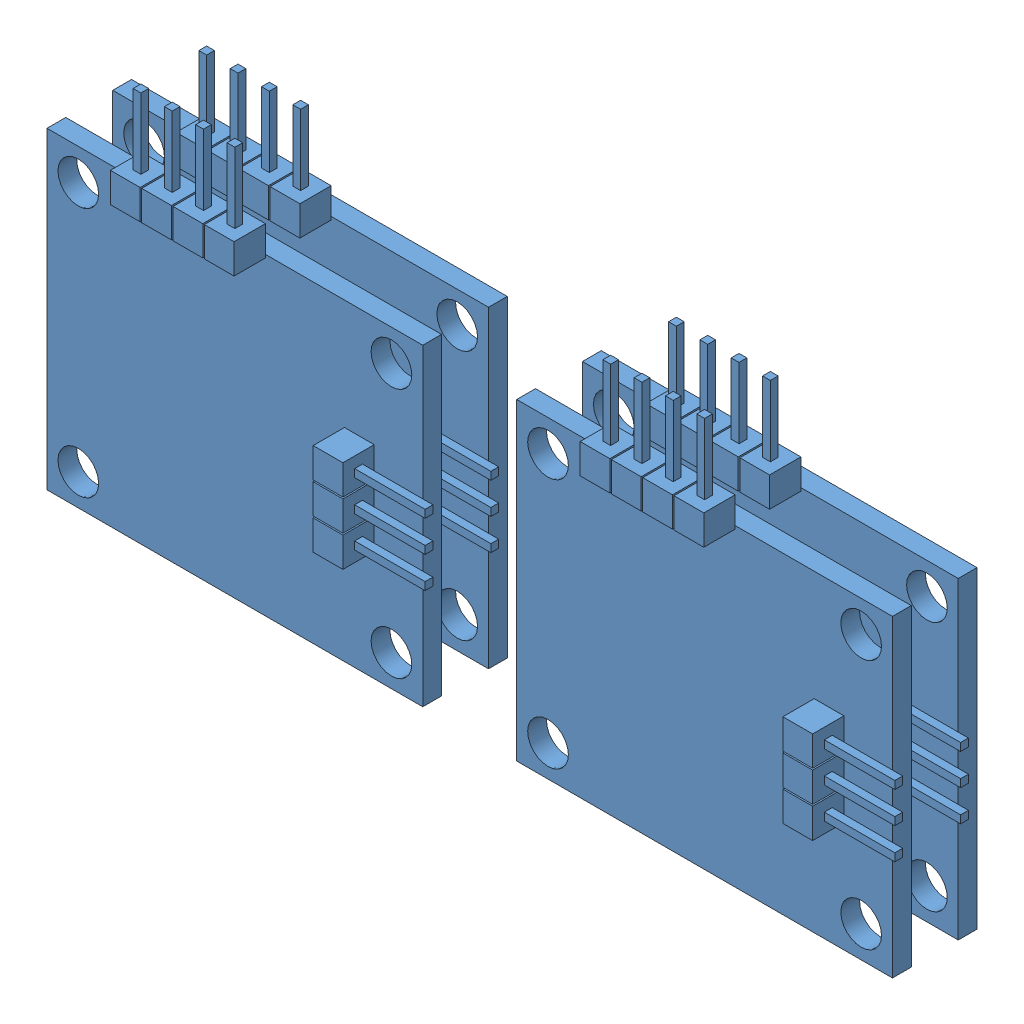
SolidWorks assembly encoderplate_group, configuration Default. Lengths in mm.
Overall size (70.36 33.27 9.4).
4 component instances, 1 part files, 57 mates.
Components (placement in the parent):
- Encoder_Plate-11: Encoder_Plate [Default] at (-18.7325 83.6117 -10.4902) x (1 0 0) z (0 1 0) size (32.26 4.06 33.27)
- Encoder_Plate-12: Encoder_Plate [Default] at (19.3675 83.6117 -10.4902) x (1 0 0) z (0 1 0) size (32.26 4.06 33.27)
- Encoder_Plate-14: Encoder_Plate [Default] at (19.3675 83.6117 -5.1562) x (1 0 0) z (0 1 0) size (32.26 4.06 33.27)
- Encoder_Plate-15: Encoder_Plate [Default] at (-18.7325 83.6117 -5.1562) x (1 0 0) z (0 1 0) size (32.26 4.06 33.27)
Mates (geometry in assembly coordinates):
- Distance6: distance = 0.254 mm: plane of ? through (120.015 18.9077 -19.2786) normal (0 0 1); plane of ? through (128.1135 64.0417 -19.0246) normal (0 0 -1)
- Concentric26: concentric: cylinder of ? through (126.2194 2.8012 -101.8286) axis (0 1 0) radius 2.159; cylinder of ? through (126.2194 6.0016 -101.8286) axis (0 1 0) radius 2.159
- Concentric27: concentric: cylinder of ? through (126.2194 2.8012 -38.3286) axis (0 1 0) radius 2.159; cylinder of ? through (126.2194 6.0016 -38.3286) axis (0 1 0) radius 2.159
- Concentric28: concentric: cylinder of ? through (-6.2035 2.8012 -101.8286) axis (0 1 0) radius 2.159; cylinder of ? through (-6.2035 6.0016 -101.8286) axis (0 1 0) radius 2.159
- Concentric29: concentric: cylinder of ? through (-6.2035 2.8012 -38.3286) axis (0 1 0) radius 2.159; cylinder of ? through (-6.2035 6.0016 -38.3286) axis (0 1 0) radius 2.159
- Coincident53: coincident: plane of ? through (130.9819 25.7073 -19.2786) normal (0 1 0); plane of ? through (135.1729 25.7073 -120.8786) normal (0 -1 0)
- Concentric30: concentric: cylinder of ? through (126.2194 6.0016 -38.3286) axis (0 1 0) radius 2.159; cylinder of ? through (126.2194 19.6008 -38.3286) axis (0 1 0) radius 2.159
- Concentric31: concentric: cylinder of ? through (126.2194 6.0016 -101.8286) axis (0 1 0) radius 2.159; cylinder of ? through (126.2194 19.6008 -101.8286) axis (0 1 0) radius 2.159
- Concentric32: concentric: cylinder of ? through (-6.2035 6.0016 -38.3286) axis (0 1 0) radius 2.159; cylinder of ? through (-6.2035 19.6008 -38.3286) axis (0 1 0) radius 2.159
- Concentric33: concentric: cylinder of ? through (-6.2035 6.0016 -101.8286) axis (0 1 0) radius 2.159; cylinder of ? through (-6.2035 19.6008 -101.8286) axis (0 1 0) radius 2.159
- Concentric47: concentric: circle of ?; cylinder of ? through (126.4745 80.5358 -4.1402) axis (0 0 -1) radius 14.224
- Coincident69: coincident: plane of ? through (128.1135 64.0417 0) normal (0 0 -1); plane of ? through (126.4745 80.5358 0) normal (0 0 1)
- Distance15: distance = 1.27 mm: plane of ?; plane of ? through (-16.046 8.9077 -120.8786) normal (0 -1 0)
- Coincident75: coincident: plane of ? through (128.1135 64.0417 -19.0246) normal (0 0 -1); plane of ? through (107.315 18.9078 -19.0246) normal (0 0 1)
- Coincident76: coincident: plane of ? through (128.1135 64.0417 -19.0246) normal (0 0 -1); plane of ? through (12.7 18.9078 -19.0246) normal (0 0 1)
- Coincident77: coincident: plane of ? through (130.7279 25.7073 -120.8786) normal (0 -1 0); plane of ? through (114.1146 25.7073 -19.0246) normal (0 1 0)
- Coincident78: coincident: plane of ? through (130.7279 25.7073 -120.8786) normal (0 -1 0); plane of ? through (19.4996 25.7073 -19.0246) normal (0 1 0)
- Coincident80: coincident: plane of ? through (128.1135 64.0417 -19.0246) normal (0 0 -1); plane of ? through (111.5009 18.9078 -19.0246) normal (0 0 1)
- Parallel8: parallel: plane of ? through (0 0 -15.8242) normal (0 -1 0); plane of ? through (116.2634 12.1082 -19.0246) normal (0 -1 0)
- Coincident82: coincident: plane of ? through (128.1135 64.0417 -19.0246) normal (0 0 -1); plane of ? through (12.7 18.9078 -19.0246) normal (0 0 1)
- Parallel9: parallel: plane of ? through (0 0 -15.8242) normal (0 -1 0); plane of ? through (17.4625 12.1082 -19.0246) normal (0 -1 0)
- Coincident85: coincident: plane of ? through (116.2634 25.7073 -19.0246) normal (0 1 0); plane of ? through (135.1729 25.7073 -120.8786) normal (0 -1 0)
- Concentric64: concentric: cylinder of ? through (12.7 7.2229 -98.6536) axis (0 1 0) radius 1.7272; cylinder of ? through (12.7 19.6008 -98.6536) axis (0 1 0) radius 2.159
- Coincident86: coincident: plane of ? through (-10.966 25.7073 -120.8786) normal (0 1 0); plane of ? through (135.1729 25.7073 -120.8786) normal (0 -1 0)
- Concentric66: concentric: cylinder of ? through (-6.2035 6.0016 -101.8286) axis (0 1 0) radius 2.159; cylinder of ? through (-6.2035 19.6008 -101.8286) axis (0 1 0) radius 2.159
- Concentric67: concentric: cylinder of ? through (-6.2035 6.0016 -38.3286) axis (0 1 0) radius 2.159; cylinder of ? through (-6.2035 19.6008 -38.3286) axis (0 1 0) radius 2.159
- Coincident87: coincident: plane of ? through (130.9819 25.7073 -19.2786) normal (0 1 0); plane of ? through (135.1729 25.7073 -120.8786) normal (0 -1 0)
- Parallel13: parallel: plane of ? through (130.727 25.7073 -120.8786) normal (0 -1 0); plane of ? through (11.2209 17.8333 -145.5881) normal (0 -1 0)
- Parallel14: parallel: plane of ? through (45.1942 -39.6262 -89.1286) normal (1 0 0); plane of ? through (36.3669 17.8333 -105.4561) normal (1 0 0)
- Distance17: distance = 6.35 mm: plane of ? through (130.727 25.7073 -120.8786) normal (0 -1 0); plane of ? through (11.2209 19.3573 -145.5881) normal (0 1 0)
- Distance18: distance = 6.35 mm: plane of ? through (130.727 25.7073 -120.8786) normal (0 -1 0); plane of ? through (18.4295 19.3573 -79.1462) normal (0 1 0)
- Distance19: distance = 6.35 mm: plane of ? through (128.1135 64.0417 -15.8242) normal (0 0 1); plane of ? through (50.5665 58.7321 -9.4742) normal (0 0 -1)
- Parallel16: parallel: plane of ? through (113.9825 55.9257 0) normal (0 1 0); plane of ? through (10.4345 83.8781 -7.9502) normal (0 1 0)
- Concentric72: concentric: cylinder of ? through (48.5005 81.8051 -22.2575) axis (0 0 1) radius 1.143; cylinder of ? through (48.5005 81.8051 -7.9502) axis (0 0 -1) radius 1.143
- Coincident89: coincident: plane of ? through (128.1135 64.0417 0) normal (0 0 -1); plane of ? through (126.4745 80.5358 0) normal (0 0 1)
- Coincident90: coincident: plane of ? through (50.5665 58.7321 -7.9502) normal (0 0 1); plane of ? through (17.1395 90.8665 -7.9502) normal (0 0 1)
- Parallel19: parallel: plane of ? through (10.4345 83.8781 -7.9502) normal (0 1 0); plane of ? through (17.1395 90.8665 -9.4742) normal (0 1 0)
- Distance24: distance = 3.81 mm: plane of ? through (128.1135 64.0417 -15.8242) normal (0 0 1); plane of ? through (1.6124 73.6376 -12.0142) normal (0 0 -1)
- Parallel21: parallel: plane of ? through (113.9825 55.9257 0) normal (0 1 0); plane of ? through (1.6124 73.6376 -10.4902) normal (0 -1 0)
- Distance31: distance = 3.81 mm: plane of ? through (128.1135 64.0417 -15.8242) normal (0 0 1); plane of Encoder_Plate-11 through (-18.7325 83.6117 -12.0142) normal (0 0 -1)
- Parallel28: parallel: plane of ? through (113.9825 55.9257 0) normal (0 1 0); plane of Encoder_Plate-11 through (-18.7325 58.2117 -12.0142) normal (0 -1 0)
- Coincident126: coincident: plane of Encoder_Plate-11 through (-18.7325 83.6117 -10.4902) normal (0 0 1); plane of Encoder_Plate-12 through (19.3675 83.6117 -10.4902) normal (0 0 1)
- Coincident127: coincident: plane of Encoder_Plate-11 through (-18.7325 58.2117 -12.0142) normal (0 -1 0); plane of Encoder_Plate-12 through (19.3675 58.2117 -12.0142) normal (0 -1 0)
- Distance32: distance = 3.81 mm: plane of Encoder_Plate-12 through (19.3675 83.6117 -10.4902) normal (0 0 1); plane of Encoder_Plate-14 through (19.3675 83.6117 -6.6802) normal (0 0 -1)
- Coincident130: coincident: plane of Encoder_Plate-12 through (19.3675 58.2117 -12.0142) normal (-1 0 0); plane of Encoder_Plate-14 through (19.3675 58.2117 -6.6802) normal (-1 0 0)
- Coincident131: coincident: plane of Encoder_Plate-12 through (19.3675 83.6117 -12.0142) normal (0 1 0); plane of Encoder_Plate-14 through (19.3675 83.6117 -6.6802) normal (0 1 0)
- Coincident132: coincident: plane of Encoder_Plate-14 through (19.3675 83.6117 -5.1562) normal (0 0 1); plane of Encoder_Plate-15 through (-18.7325 83.6117 -5.1562) normal (0 0 1)
- Coincident133: coincident: plane of Encoder_Plate-11 through (-18.7325 58.2117 -12.0142) normal (-1 0 0); plane of Encoder_Plate-15 through (-18.7325 58.2117 -6.6802) normal (-1 0 0)
- Coincident134: coincident: plane of Encoder_Plate-11 through (-18.7325 83.6117 -12.0142) normal (0 1 0); plane of Encoder_Plate-15 through (-18.7325 83.6117 -6.6802) normal (0 1 0)
- Distance34: distance = 6.35 mm: plane of ? through (36.692 35.2577 -91.9532) normal (0 -1 0); plane of ? through (135.1729 28.9077 -120.8786) normal (0 1 0)
- Concentric74: concentric: cylinder of ? through (21.9075 81.0717 -22.2216) axis (0 0 1) radius 1.1303; cylinder of Encoder_Plate-12 through (21.9075 81.0717 -12.0142) axis (0 0 1) radius 1.651
- Concentric75: concentric: cylinder of ? through (9.2075 81.0717 -22.2216) axis (0 0 1) radius 1.1303; cylinder of Encoder_Plate-11 through (9.2075 81.0717 -12.0142) axis (0 0 1) radius 1.651
- Distance35: distance = 6.35 mm: plane of ? through (135.1729 25.7073 -120.8786) normal (0 -1 0); plane of ? through (28.0575 19.3573 -56.6185) normal (0 1 0)
- Parallel33: parallel: plane of ? through (128.1135 64.0417 -19.0246) normal (0 0 -1); plane of ? through (28.0575 19.3573 -82.0185) normal (0 0 -1)
- Coincident144: coincident: plane of ? through (28.0575 17.8333 -56.6185) normal (0 -1 0); plane of ? through (90.6068 17.8333 -52.4441) normal (0 -1 0)
- Parallel34: parallel: plane of ? through (128.1135 64.0417 -19.0246) normal (0 0 -1); plane of ? through (90.6068 19.3573 -27.0441) normal (0 0 1)
- Parallel35: parallel: plane of ? through (113.9825 55.9257 0) normal (0 1 0); plane of ? through (133.777 67.7088 18.2016) normal (0 -1 0)
